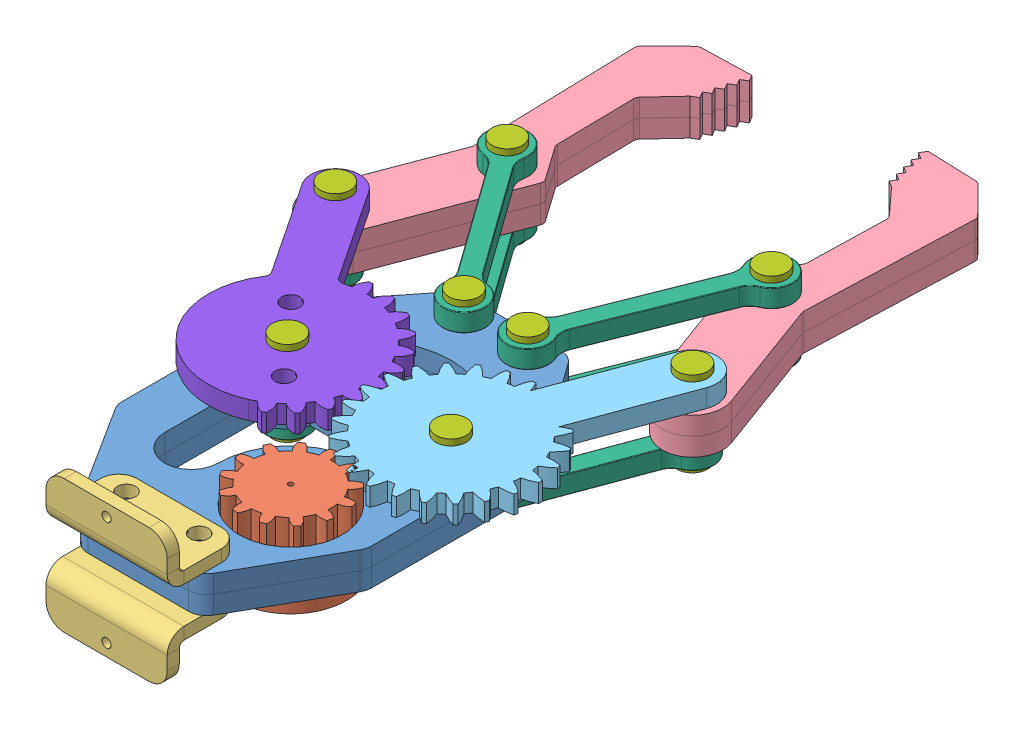
SolidWorks assembly Robot Gripper, configuration Default. Lengths in mm.
Overall size (87.93 22 129.78).
25 component instances, 8 part files, 58 mates.
Components (placement in the parent):
- Base Plate-1: Base Plate [Default] at (28.677 35.3314 42.0504) size (41.21 3 62)
- Base Plate-2: Base Plate [Default] at (28.677 38.3314 42.0504) size (41.21 3 62)
- Base Gear-1: Base Gear [Default] at (36.177 35.3314 55.4504) x (0.640501 0 -0.767958) z (0.767958 0 0.640501) size (18.5 12 18.5)
- Base Mounting Bracket-1: Base Mounting Bracket [Default] at (28.677 41.3314 66.3304) x (0 0 1) z (-1 0 0) size (12 8 20)
- Base Mounting Bracket-2: Base Mounting Bracket [Default] at (28.677 35.3314 66.3304) x (0 0 1) z (1 0 0) size (12 8 20)
- Gripper-1: Gripper [Default] at (-2.4239 38.3314 9.4947) x (0.353852 0 -0.935301) z (0.935301 0 0.353852) size (60.44 3 20.51)
- Gripper-2: Gripper [Default] at (-2.4239 35.3314 9.4947) x (0.353852 0 -0.935301) z (0.935301 0 0.353852) size (60.44 3 20.51)
- Gripper-3: Gripper [Default] at (52.9527 41.3314 5.9335) x (-0.345698 0 -0.938346) z (-0.938346 0 0.345698) size (60.44 3 20.51)
- Gripper-4: Gripper [Default] at (52.9527 38.3314 5.9335) x (-0.345698 0 -0.938346) z (-0.938346 0 0.345698) size (60.44 3 20.51)
- Gear Link 1-1: Gear Link 1 [Default] at (42.177 41.3314 35.0004) x (0.347603 0 -0.937642) z (0.937642 0 0.347603) size (49.16 3 28.33)
- link-1: link [Default] at (5.3608 41.3314 -11.0819) x (0.582779 0 0.812631) z (-0.812631 0 0.582779) size (38 3 7)
- link-2: link [Default] at (5.3608 32.3314 -11.0819) x (0.582779 0 0.812631) z (-0.812631 0 0.582779) size (38 3 7)
- link-4: link [Default] at (45.3473 41.3314 -14.7101) x (-0.368398 0 0.929668) z (-0.929668 0 -0.368398) size (38 3 7)
- pin-1: pin [Default] at (15.177 31.3314 35.0004) x (-0.704787 0 0.709419) z (-0.709419 0 -0.704787) size (5 14 5)
- link-5: link [Default] at (52.9527 32.3314 5.9335) x (-0.347603 0 0.937642) z (-0.937642 0 -0.347603) size (38 3 7)
- link-6: link [Default] at (33.927 32.3314 14.1096) x (0.368398 0 -0.929668) z (0.929668 0 0.368398) size (38 3 7)
- Gear Link 2-3: Gear Link 2 [Default] at (15.177 44.3314 35.0004) x (-0.669454 0 -0.742854) z (-0.742854 0 0.669454) size (49.64 3 27.91)
- pin-2: pin [Default] at (5.3608 31.3314 -11.0819) size (5 14 5)
- pin-3: pin [Default] at (23.427 31.3314 14.1096) size (5 14 5)
- pin-4: pin [Default] at (45.3473 31.3314 -14.7101) size (5 14 5)
- pin-5: pin [Default] at (52.9527 31.3314 5.9335) size (5 14 5)
- pin-6: pin [Default] at (33.927 31.3314 14.1096) size (5 14 5)
- pin-7: pin [Default] at (42.177 31.3314 35.0004) size (5 14 5)
- pin-8: pin [Default] at (-2.4239 31.3314 9.4947) size (5 14 5)
- link-7: link [Default] at (-2.6113 32.3314 9.6119) x (0.573816 0 0.818984) z (-0.818984 0 0.573816) size (38 3 7)
Mates (geometry in assembly coordinates):
- Coincident3: coincident: point of Base Plate-1; line of Base Plate-2 through (36.3791 38.3314 11.0504) axis (-1 0 0)
- Coincident4: coincident aligned: line of Base Plate-1 through (7.4656 38.3314 27.2111) axis (0 0 1); line of Base Plate-2 through (7.4656 38.3314 27.2111) axis (0 0 1)
- Coincident8: coincident anti-aligned: plane of Base Plate-2 through (20.8788 41.3314 14.0504) normal (0 1 0); plane of Base Mounting Bracket-1 through (21.677 41.3314 69.3304) normal (0 -1 0)
- Coincident9: coincident aligned: circle of Base Plate-2; circle of Base Mounting Bracket-1
- Coincident10: coincident aligned: circle of Base Plate-2; circle of Base Mounting Bracket-1
- Coincident11: coincident anti-aligned: plane of Base Plate-1 through (20.8788 35.3314 14.0504) normal (0 -1 0); plane of Base Mounting Bracket-2 through (35.677 35.3314 69.3304) normal (0 1 0)
- Coincident12: coincident anti-aligned: circle of Base Plate-1; circle of Base Mounting Bracket-2
- Coincident13: coincident anti-aligned: circle of Base Plate-1; circle of Base Mounting Bracket-2
- Coincident14: coincident anti-aligned: plane of Gripper-3 through (43.1605 38.3314 -21.7829) normal (0 -1 0); plane of Gripper-4 through (43.1605 38.3314 -21.7829) normal (0 1 0)
- Coincident15: coincident aligned: plane of Gripper-3 through (48.2609 38.3314 7.662) normal (-0.938346 0 0.345698); plane of Gripper-4 through (48.2609 35.3314 7.662) normal (-0.938346 0 0.345698)
- Concentric2: concentric aligned: cylinder of Gripper-3 through (52.9527 38.3314 5.9335) axis (0 1 0) radius 5; cylinder of Gripper-4 through (52.9527 35.3314 5.9335) axis (0 1 0) radius 5
- Coincident16: coincident aligned: plane of Gripper-1 through (-0.0821 41.3314 -11.0378) normal (-0.999597 0 0.02839); plane of Gripper-2 through (-0.0821 38.3314 -11.0378) normal (-0.999597 0 0.02839)
- Concentric3: concentric aligned: cylinder of Gripper-1 through (-2.4239 41.3314 9.4947) axis (0 -1 0) radius 5; cylinder of Gripper-2 through (-2.4239 38.3314 9.4947) axis (0 -1 0) radius 5
- Concentric4: concentric aligned: cylinder of Gripper-1 through (5.3608 41.3314 -11.0819) axis (0 -1 0) radius 1.5; cylinder of Gripper-2 through (5.3608 38.3314 -11.0819) axis (0 -1 0) radius 1.5
- Coincident24: coincident anti-aligned: plane of Gripper-1 through (7.6091 38.3314 -18.1354) normal (0 -1 0); plane of Gripper-2 through (7.6091 38.3314 -18.1354) normal (0 1 0)
- Concentric5: concentric aligned: cylinder of Gripper-1 through (5.3608 41.3314 -11.0819) axis (0 -1 0) radius 1.5; cylinder of link-1 through (5.3608 44.3314 -11.0819) axis (0 -1 0) radius 1.5
- Coincident27: coincident anti-aligned: plane of Gripper-1 through (7.6091 41.3314 -18.1354) normal (0 1 0); plane of link-1 through (5.3608 41.3314 -11.0819) normal (0 -1 0)
- Concentric6: concentric aligned: cylinder of Base Plate-2 through (23.427 41.3314 14.1096) axis (0 -1 0) radius 1.5; cylinder of link-1 through (23.427 44.3314 14.1096) axis (0 -1 0) radius 1.5
- Coincident28: coincident anti-aligned: plane of Gripper-2 through (7.6091 35.3314 -18.1354) normal (0 -1 0); plane of link-2 through (5.3608 35.3314 -11.0819) normal (0 1 0)
- Concentric7: concentric aligned: cylinder of Gripper-2 through (5.3608 38.3314 -11.0819) axis (0 -1 0) radius 1.5; cylinder of link-2 through (5.3608 35.3314 -11.0819) axis (0 -1 0) radius 1.5
- Concentric8: concentric aligned: cylinder of Base Plate-1 through (23.427 38.3314 14.1096) axis (0 -1 0) radius 1.5; cylinder of link-2 through (23.427 35.3314 14.1096) axis (0 -1 0) radius 1.5
- Concentric24: concentric anti-aligned: cylinder of Gripper-3 through (45.3473 38.3314 -14.7101) axis (0 1 0) radius 1.5; cylinder of link-4 through (45.3473 44.3314 -14.7101) axis (0 -1 0) radius 1.5
- Coincident31: coincident anti-aligned: plane of Gripper-3 through (43.1605 41.3314 -21.7829) normal (0 1 0); plane of link-4 through (45.3473 41.3314 -14.7101) normal (0 -1 0)
- Concentric25: concentric aligned: cylinder of Base Plate-2 through (33.927 41.3314 14.1096) axis (0 -1 0) radius 1.5; cylinder of link-4 through (33.927 44.3314 14.1096) axis (0 -1 0) radius 1.5
- Coincident32: coincident anti-aligned: plane of Gripper-4 through (43.1605 35.3314 -21.7829) normal (0 -1 0); plane of link-5 through (52.9527 35.3314 5.9335) normal (0 1 0)
- Concentric26: concentric anti-aligned: cylinder of Gripper-4 through (52.9527 35.3314 5.9335) axis (0 1 0) radius 1.5; cylinder of link-5 through (52.9527 35.3314 5.9335) axis (0 -1 0) radius 1.5
- Concentric27: concentric aligned: cylinder of Base Plate-1 through (42.177 38.3314 35.0004) axis (0 -1 0) radius 1.5; cylinder of link-5 through (42.177 35.3314 35.0004) axis (0 -1 0) radius 1.5
- Coincident33: coincident anti-aligned: plane of Gripper-4 through (43.1605 35.3314 -21.7829) normal (0 -1 0); plane of link-6 through (33.927 35.3314 14.1096) normal (0 1 0)
- Concentric28: concentric anti-aligned: cylinder of Gripper-4 through (45.3473 35.3314 -14.7101) axis (0 1 0) radius 1.5; cylinder of link-6 through (45.3473 35.3314 -14.7101) axis (0 -1 0) radius 1.5
- Concentric29: concentric aligned: cylinder of Base Plate-1 through (33.927 38.3314 14.1096) axis (0 -1 0) radius 1.5; cylinder of link-6 through (33.927 35.3314 14.1096) axis (0 -1 0) radius 1.5
- Coincident37: coincident anti-aligned: plane of Base Plate-2 through (20.8788 41.3314 14.0504) normal (0 1 0); plane of Gear Link 1-1 through (42.177 41.3314 35.0004) normal (0 -1 0)
- Concentric30: concentric aligned: cylinder of Base Plate-2 through (42.177 41.3314 35.0004) axis (0 -1 0) radius 1.5; cylinder of Gear Link 1-1 through (42.177 44.3314 35.0004) axis (0 -1 0) radius 1.5
- Concentric31: concentric anti-aligned: cylinder of Gripper-3 through (52.9527 38.3314 5.9335) axis (0 1 0) radius 1.5; cylinder of Gear Link 1-1 through (52.9527 44.3314 5.9335) axis (0 -1 0) radius 1.5
- Coincident38: coincident anti-aligned: plane of Gripper-3 through (43.1605 41.3314 -21.7829) normal (0 1 0); plane of Gear Link 1-1 through (42.177 41.3314 35.0004) normal (0 -1 0)
- Concentric32: concentric anti-aligned: circle of Base Plate-1; circle of Base Gear-1
- Coincident39: coincident anti-aligned: plane of Base Plate-1 through (20.8788 35.3314 14.0504) normal (0 -1 0); plane of Base Gear-1 through (36.177 35.3314 55.4504) normal (0 1 0)
- Coincident40: coincident anti-aligned: plane of Base Plate-2 through (20.8788 41.3314 14.0504) normal (0 1 0); plane of Gear Link 2-3 through (-6.1894 41.3314 12.7843) normal (0 -1 0)
- Concentric33: concentric anti-aligned: cylinder of Base Plate-2 through (15.177 41.3314 35.0004) axis (0 -1 0) radius 1.5; cylinder of Gear Link 2-3 through (15.177 41.3314 35.0004) axis (0 1 0) radius 1.5
- Concentric34: concentric anti-aligned: cylinder of Gripper-1 through (-2.4239 41.3314 9.4947) axis (0 -1 0) radius 1.5; cylinder of Gear Link 2-3 through (-2.4239 41.3314 9.4947) axis (0 1 0) radius 1.5
- Coincident41: coincident anti-aligned: plane of pin-1 through (15.177 44.3314 35.0004) normal (0 -1 0); plane of Gear Link 2-3 through (-6.1894 44.3314 12.7843) normal (0 1 0)
- Concentric35: concentric anti-aligned: cylinder of pin-1 through (15.177 44.3314 35.0004) axis (0 -1 0) radius 1.5; cylinder of Gear Link 2-3 through (15.177 41.3314 35.0004) axis (0 1 0) radius 1.5
- Coincident42: coincident anti-aligned: plane of link-1 through (5.3608 44.3314 -11.0819) normal (0 1 0); plane of pin-2 through (5.3608 44.3314 -11.0819) normal (0 -1 0)
- Concentric36: concentric aligned: cylinder of link-1 through (5.3608 44.3314 -11.0819) axis (0 -1 0) radius 1.5; cylinder of pin-2 through (5.3608 44.3314 -11.0819) axis (0 -1 0) radius 1.5
- Concentric37: concentric aligned: cylinder of link-4 through (45.3473 44.3314 -14.7101) axis (0 -1 0) radius 1.5; cylinder of pin-4 through (45.3473 44.3314 -14.7101) axis (0 -1 0) radius 1.5
- Coincident43: coincident anti-aligned: plane of link-4 through (45.3473 44.3314 -14.7101) normal (0 1 0); plane of pin-4 through (45.3473 44.3314 -14.7101) normal (0 -1 0)
- Concentric38: concentric aligned: cylinder of Gear Link 1-1 through (52.9527 44.3314 5.9335) axis (0 -1 0) radius 1.5; cylinder of pin-5 through (52.9527 44.3314 5.9335) axis (0 -1 0) radius 1.5
- Coincident44: coincident anti-aligned: plane of Gear Link 1-1 through (42.177 44.3314 35.0004) normal (0 1 0); plane of pin-5 through (52.9527 44.3314 5.9335) normal (0 -1 0)
- Coincident45: coincident anti-aligned: plane of link-1 through (5.3608 44.3314 -11.0819) normal (0 1 0); plane of pin-3 through (23.427 44.3314 14.1096) normal (0 -1 0)
- Concentric39: concentric aligned: cylinder of link-1 through (23.427 44.3314 14.1096) axis (0 -1 0) radius 1.5; cylinder of pin-3 through (23.427 44.3314 14.1096) axis (0 -1 0) radius 1.5
- Coincident46: coincident anti-aligned: plane of link-4 through (45.3473 44.3314 -14.7101) normal (0 1 0); plane of pin-6 through (33.927 44.3314 14.1096) normal (0 -1 0)
- Concentric40: concentric aligned: cylinder of link-4 through (33.927 44.3314 14.1096) axis (0 -1 0) radius 1.5; cylinder of pin-6 through (33.927 44.3314 14.1096) axis (0 -1 0) radius 1.5
- Concentric41: concentric aligned: cylinder of Gear Link 1-1 through (42.177 44.3314 35.0004) axis (0 -1 0) radius 1.5; cylinder of pin-7 through (42.177 44.3314 35.0004) axis (0 -1 0) radius 1.5
- Coincident47: coincident anti-aligned: plane of Gear Link 1-1 through (42.177 44.3314 35.0004) normal (0 1 0); plane of pin-7 through (42.177 44.3314 35.0004) normal (0 -1 0)
- Coincident48: coincident anti-aligned: plane of Gripper-2 through (7.6091 35.3314 -18.1354) normal (0 -1 0); plane of link-7 through (-2.6113 35.3314 9.6119) normal (0 1 0)
- Concentric42: concentric aligned: cylinder of pin-1 through (15.177 44.3314 35.0004) axis (0 -1 0) radius 1.5; cylinder of link-7 through (15.177 35.3314 35.0004) axis (0 -1 0) radius 1.5
- Concentric43: concentric anti-aligned: cylinder of Gear Link 2-3 through (-2.4239 41.3314 9.4947) axis (0 1 0) radius 1.5; cylinder of pin-8 through (-2.4239 44.3314 9.4947) axis (0 -1 0) radius 1.5
- Coincident49: coincident anti-aligned: plane of Base Plate-1 through (20.8788 35.3314 14.0504) normal (0 -1 0); plane of link-7 through (-2.6113 35.3314 9.6119) normal (0 1 0)
- Coincident50: coincident anti-aligned: plane of Gear Link 2-3 through (-6.1894 44.3314 12.7843) normal (0 1 0); plane of pin-8 through (-2.4239 44.3314 9.4947) normal (0 -1 0)
